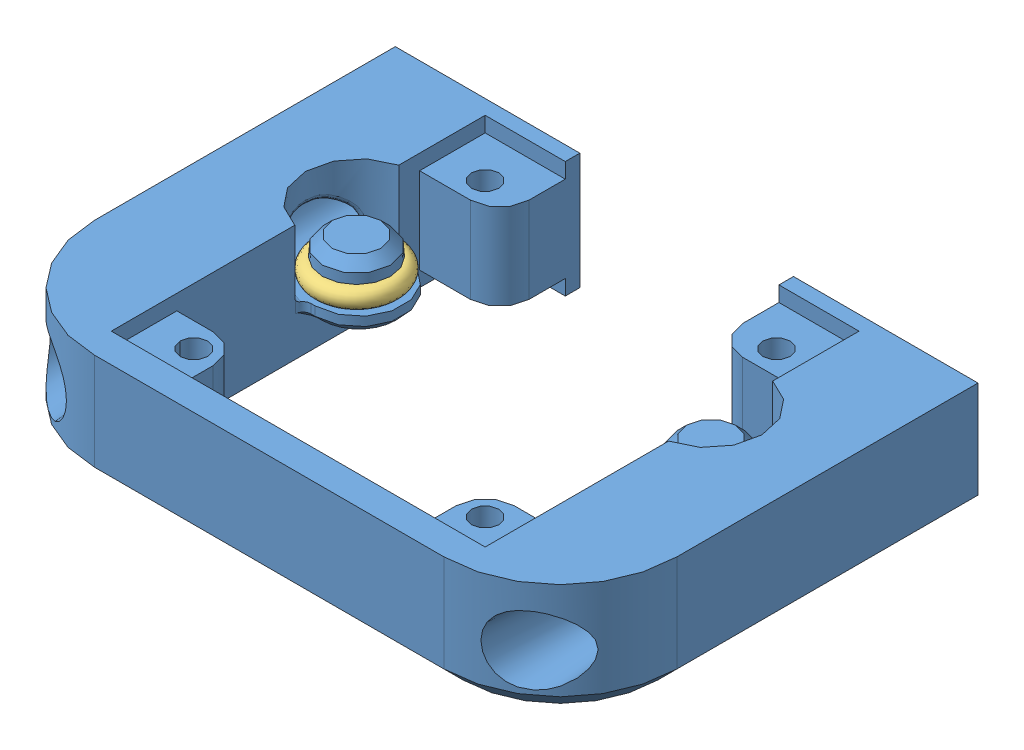
SolidWorks assembly printed_base_assembly, configuration Default. Lengths in mm.
Overall size (102.25 179.33 88.2).
5 component instances, 3 part files, 8 mates.
Components (placement in the parent):
- printed_base-1: printed_base [Printed Lower Base] at (21.8985 46.0688 -8.4198)
- m3_heat_set_insert_94180A331-1: m3_heat_set_insert_94180A331 [94180A331] at (7.8985 78.5688 -5.4198) x (0.928039 0.372484 0) z (-0.372484 0.928039 0)
- m3_heat_set_insert_94180A331-2: m3_heat_set_insert_94180A331 [94180A331] at (35.8985 78.5688 -5.4198) x (0.997541 -0.070079 0) z (0.070079 0.997541 0)
- 5x9x2_oring-1: 5x9x2_oring [Default] at (3.6485 78.0688 10.3302) x (0.994492 0 -0.104809) z (0.104809 0 0.994492)
- 5x9x2_oring-2: 5x9x2_oring [Default] at (40.1485 78.0688 10.3302) x (-0.984669 0 0.174435) z (-0.174435 0 -0.984669)
Mates (geometry in assembly coordinates):
- Concentric1084: concentric aligned: cylinder of printed_base-1 through (7.8985 78.5688 -1.4198) axis (0 0 -1) radius 2.55; cylinder of m3_heat_set_insert_94180A331-1 through (7.8985 78.5688 -5.1658) axis (0 0 -1) radius 2.78
- Coincident725: coincident aligned: plane of printed_base-1 through (-8.1015 72.0688 -5.4198) normal (0 0 -1); plane of m3_heat_set_insert_94180A331-1 through (7.8985 78.5688 -5.4198) normal (0 0 -1)
- Concentric1085: concentric aligned: cylinder of printed_base-1 through (35.8985 78.5688 -1.4198) axis (0 0 -1) radius 2.55; cylinder of m3_heat_set_insert_94180A331-2 through (35.8985 78.5688 -5.1658) axis (0 0 -1) radius 2.78
- Coincident726: coincident aligned: plane of printed_base-1 through (-8.1015 72.0688 -5.4198) normal (0 0 -1); plane of m3_heat_set_insert_94180A331-2 through (35.8985 78.5688 -5.4198) normal (0 0 -1)
- Concentric1086: concentric anti-aligned: cylinder of printed_base-1 through (3.6485 77.0688 10.3302) axis (0 -1 0) radius 3.5; line of 5x9x2_oring-1 through (3.6485 78.0688 10.3302) axis (0 1 0)
- Concentric1087: concentric anti-aligned: cylinder of printed_base-1 through (40.1485 77.0688 10.3302) axis (0 -1 0) radius 3.5; line of 5x9x2_oring-2 through (40.1485 78.0688 10.3302) axis (0 1 0)
- Coincident727: coincident: torus of printed_base-1; point of 5x9x2_oring-2
- Coincident730: coincident: edge_curve of printed_base-1
